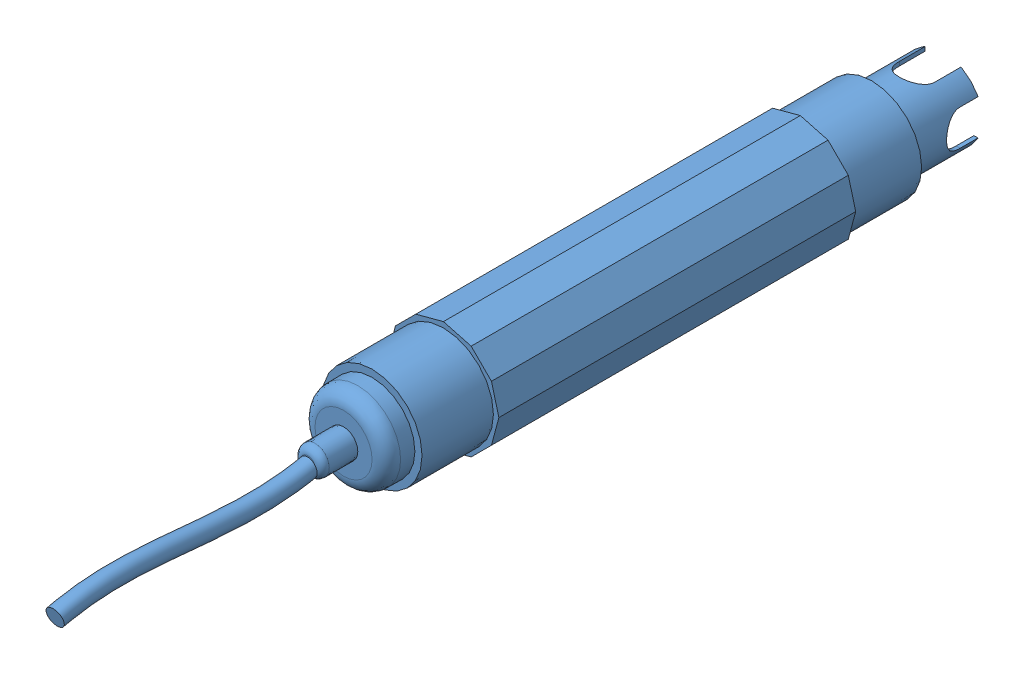
SolidWorks assembly pH_Sensor, configuration Default. Lengths in mm.
Overall size (31.06 31.06 178).
2 component instances, 2 part files, 2 mates.
Components (placement in the parent):
- pH_Sensor-1: pH_Sensor [Default] at (-41.0008 3.6256 55.1724) size (31.06 31.06 178)
- pH_Sensor_pipe-1: pH_Sensor_pipe [Default] at (-41.0008 3.6256 55.1724) x (0.989202 0.146557 0) z (0 0 1) (suppressed, hidden)
Mates (geometry in assembly coordinates):
- Concentric1: concentric aligned: cylinder of pH_Sensor-1 through (-41.0008 3.6256 75.1724) axis (0 0 -1) radius 14; cylinder of pH_Sensor_pipe-1 through (-41.0008 3.6256 155.1724) axis (0 0 -1) radius 14
- Coincident1: coincident anti-aligned: plane of pH_Sensor-1 through (-41.0008 3.6256 55.1724) normal (0 0 1); plane of pH_Sensor_pipe-1 through (-41.0008 3.6256 55.1724) normal (0 0 -1)
